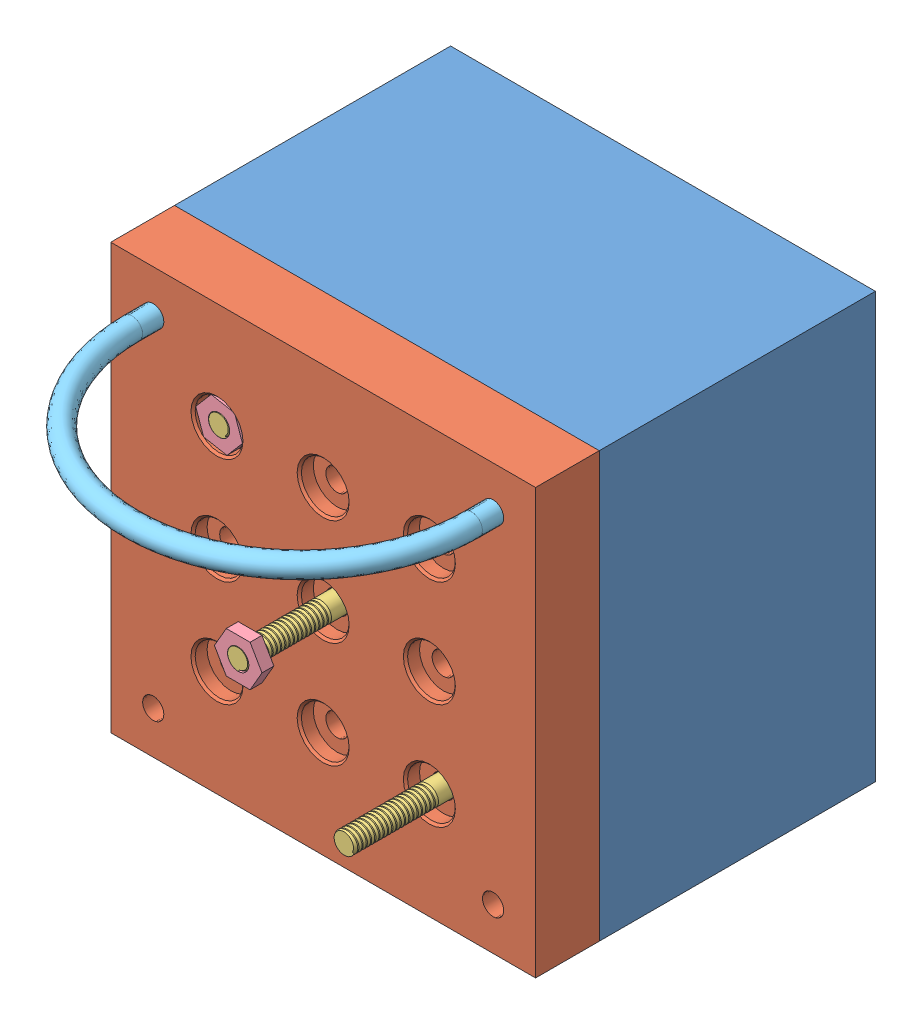
SolidWorks assembly Block_Support_Concept, configuration Default. Lengths in mm.
Overall size (127 127 187.96).
8 component instances, 5 part files, 16 mates.
Components (placement in the parent):
- Anchorage-1: Anchorage [Default] at origin size (127 127 82.55)
- Bearing_Plate-1: Bearing_Plate [Default] at (0 0 82.55) size (127 127 19.05)
- rod_threaded-1: rod_threaded [Default] at (31.75 -31.75 0) x (0.806781 -0.590851 0) z (0 0 1) size (6.35 6.52 128.07)
- rod_threaded-2: rod_threaded [Default] at (-31.75 31.75 -26.035) x (0.542093 -0.840318 0) z (0 0 1) size (6.35 6.52 128.07)
- rod_threaded-3: rod_threaded [Default] x (-0.102855 -0.994696 0) z (0 0 1) size (6.35 6.52 128.07)
- nut-1: nut [Default] at (-31.75 31.75 97.409) x (0.33382 -0.942637 0) z (0 0 1) size (14.22 12.32 3.56)
- nut-2: nut [Default] at (0 0 123.444) size (14.22 12.32 3.56)
- U_Bolts-1: U_Bolts [Default] at (0 50.8 107.95) x (1 0 0) z (0 -1 0) size (107.95 79.38 6.35)
Mates (geometry in assembly coordinates):
- Coincident1: coincident aligned: plane of Anchorage-1 through (-63.5 63.5 82.55) normal (0 1 0); plane of Bearing_Plate-1 through (-63.5 63.5 101.6) normal (0 1 0)
- Coincident2: coincident aligned: plane of Anchorage-1 through (63.5 -63.5 82.55) normal (1 0 0); plane of Bearing_Plate-1 through (63.5 -63.5 101.6) normal (1 0 0)
- Coincident3: coincident anti-aligned: plane of Anchorage-1 through (0 0 82.55) normal (0 0 1); plane of Bearing_Plate-1 through (0 0 82.55) normal (0 0 -1)
- Concentric1: concentric anti-aligned: cylinder of Bearing_Plate-1 through (-31.75 31.75 101.6) axis (0 0 1) radius 3.3782; cylinder of rod_threaded-2 through (-31.75 31.75 100.965) axis (0 0 -1) radius 3.175
- Concentric2: concentric anti-aligned: cylinder of Bearing_Plate-1 through (0 0 101.6) axis (0 0 1) radius 3.3782; cylinder of rod_threaded-3 through (0 0 127) axis (0 0 -1) radius 3.175
- Concentric3: concentric anti-aligned: cylinder of Bearing_Plate-1 through (31.75 -31.75 101.6) axis (0 0 1) radius 3.3782; cylinder of rod_threaded-1 through (31.75 -31.75 127) axis (0 0 -1) radius 3.175
- Concentric4: concentric aligned: cylinder of rod_threaded-2 through (-31.75 31.75 100.965) axis (0 0 -1) radius 3.175; cylinder of nut-1 through (-31.75 31.75 100.965) axis (0 0 -1) radius 3.175
- Coincident4: coincident aligned: plane of rod_threaded-2 through (-31.75 31.75 100.965) normal (0 0 1); plane of nut-1 through (-31.75 31.75 100.965) normal (0 0 1)
- Coincident5: coincident anti-aligned: plane of Bearing_Plate-1 through (-24.6062 31.75 97.409) normal (0 0 1); plane of nut-1 through (-31.75 31.75 97.409) normal (0 0 -1)
- Coincident6: coincident anti-aligned: cylinder of rod_threaded-3 through (0 0 127) axis (0 0 -1) radius 3.175; circle of nut-2
- Coincident7: coincident aligned: plane of rod_threaded-3 through (0 0 127) normal (0 0 1); plane of nut-2 through (0 0 127) normal (0 0 1)
- Coincident8: coincident aligned: plane of Anchorage-1 through (0 0 0) normal (0 0 -1); plane of rod_threaded-1 through (31.75 -31.75 0) normal (0 0 -1)
- Coincident9: coincident aligned: plane of Anchorage-1 through (0 0 0) normal (0 0 -1); plane of rod_threaded-3 through (0 0 0) normal (0 0 -1)
- Concentric5: concentric aligned: cylinder of Bearing_Plate-1 through (50.8 50.8 101.6) axis (0 0 1) radius 3.175; cylinder of U_Bolts-1 through (50.8 50.8 82.55) axis (0 0 1) radius 3.175
- Concentric6: concentric aligned: cylinder of Bearing_Plate-1 through (-50.8 50.8 101.6) axis (0 0 1) radius 3.175; cylinder of U_Bolts-1 through (-50.8 50.8 82.55) axis (0 0 1) radius 3.175
- Coincident10: coincident anti-aligned: circle of Anchorage-1; circle of U_Bolts-1
